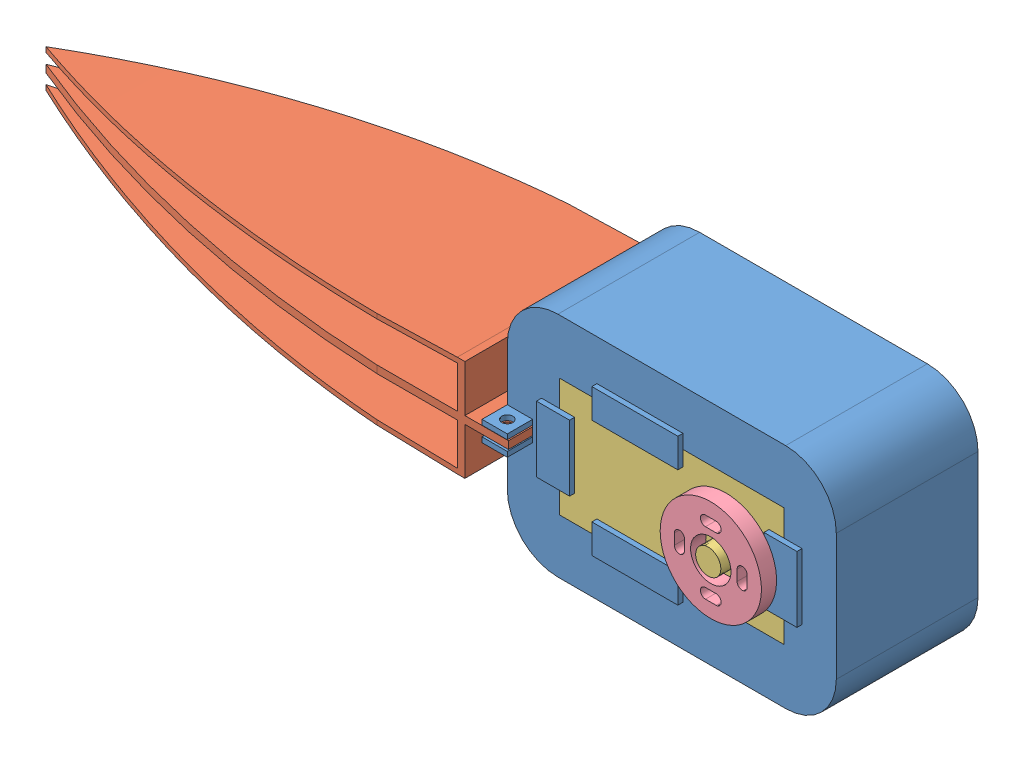
SolidWorks assembly link6, configuration 預設. Lengths in mm.
Overall size (170.1 45 38.21).
5 component instances, 4 part files, 12 mates.
Components (placement in the parent):
- bus2_tail-2: bus2_tail [預設] at (-9.0934 -16.9047 37.067) size (65 45 38)
- bus_final_tail-2: bus_final_tail [預設] at (-73.1187 -16.9047 50.3365) x (-1 0 0.00071) z (0 1 0) size (110.1 38.13 25.31)
- bus_servo-4: bus_servo [預設] at (-16.5803 -28.3978 37.067) x (1 0 0) z (0 -1 0) size (44.4 38 23.4)
- bus_servo_cicrcle1-1: bus_servo_cicrcle1 [預設] at (-24.328 -16.9047 66.567) size (20 20 3)
- bus_servo_cicrcle1-2: bus_servo_cicrcle1 [預設] at (-24.328 -16.9047 32.567) size (20 20 3)
Mates (geometry in assembly coordinates):
- 重合/共線/共點11: coincident: plane of bus2_tail-2 through (-58.728 -28.6047 76.067) normal (0 1 0); plane of bus_servo-4 through (-58.728 -28.6047 65.067) normal (0 -1 0)
- 重合/共線/共點12: coincident: plane of bus2_tail-2 through (-14.328 -5.2047 76.067) normal (-1 0 0); plane of bus_servo-4 through (-14.328 -5.2047 65.067) normal (1 0 0)
- 重合/共線/共點13: coincident: plane of bus2_tail-2 through (-9.0934 -16.9047 65.067) normal (0 0 1); plane of bus_servo-4 through (-16.5803 -28.3978 65.067) normal (0 0 1)
- 同軸心6: concentric: cylinder of bus2_tail-2 through (-66.528 -11.9047 67.567) axis (0 -1 0) radius 1.1; cylinder of bus_final_tail-2 through (-66.528 -17.6547 67.567) axis (0 1 0) radius 1.1
- 同軸心7: concentric: cylinder of bus2_tail-2 through (-66.528 -11.9047 34.567) axis (0 -1 0) radius 1.1; cylinder of bus_final_tail-2 through (-66.528 -17.6547 34.567) axis (0 1 0) radius 1.1
- 平行相距7: distance = 0.25 mm: plane of bus_final_tail-2 through (-73.1187 -17.6547 50.3365) normal (0 -1 0); plane of bus2_tail-2 through (-9.0934 -17.9047 37.067) normal (0 1 0)
- 同軸心9: concentric: cylinder of bus_servo-4 through (-24.328 -16.9047 65.067) axis (0 0 1) radius 2.5; cylinder of bus_servo_cicrcle1-1 through (-24.328 -16.9047 70.567) axis (0 0 -1) radius 4
- 平行4: parallel: plane of bus2_tail-2 through (-4.028 5.5953 65.067) normal (1 0 0); plane of bus_servo_cicrcle1-1 through (-17.128 -15.8547 70.567) normal (-1 0 0)
- 平行相距8: distance = 0.5 mm: plane of bus_servo-4 through (-24.328 -16.9047 70.067) normal (0 0 1); plane of bus_servo_cicrcle1-1 through (-24.328 -16.9047 69.567) normal (0 0 1)
- 同軸心10: concentric: cylinder of bus_servo-4 through (-24.328 -16.9047 32.067) axis (0 0 1) radius 2.5; cylinder of bus_servo_cicrcle1-2 through (-24.328 -16.9047 36.567) axis (0 0 -1) radius 4
- 平行5: parallel: plane of bus2_tail-2 through (-4.028 5.5953 65.067) normal (1 0 0); plane of bus_servo_cicrcle1-2 through (-17.128 -15.8547 36.567) normal (-1 0 0)
- 平行相距10: distance = 0.5 mm: plane of bus_servo-4 through (-24.328 -16.9047 32.067) normal (0 0 -1); plane of bus_servo_cicrcle1-2 through (-24.328 -16.9047 32.567) normal (0 0 -1)
